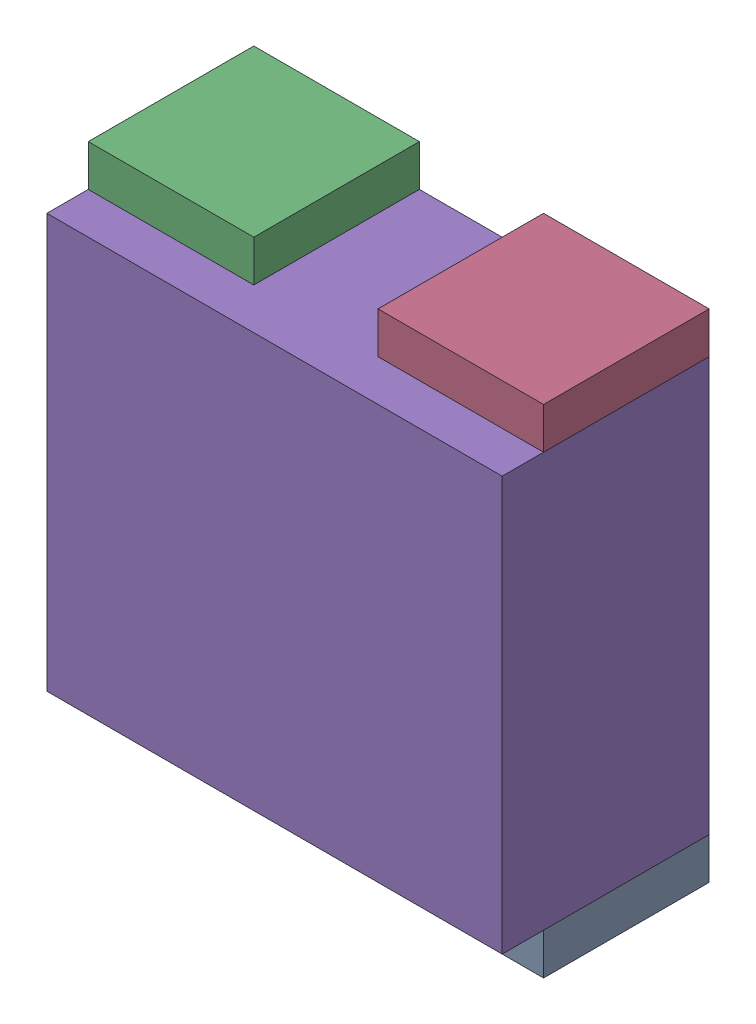
SolidWorks assembly RN12, configuration Default. Lengths in mm.
Overall size (1.1 1.2 0.5).
10 component instances, 2 part files, 0 mates.
Components (placement in the parent):
- 810157616-1: 810157616 [Default] at (123.35 53.35 0) size (0.4 0.1 0.4)
  - Extruded_12-1: Extruded_12 [Default] at origin size (0.4 0.1 0.4)
- 810157616-2: 810157616 [Default] at (122.65 53.35 0) size (0.4 0.1 0.4)
  - Extruded_12-1: Extruded_12 [Default] at origin size (0.4 0.1 0.4)
- 810157616-3: 810157616 [Default] at (122.65 54.45 0) size (0.4 0.1 0.4)
  - Extruded_12-1: Extruded_12 [Default] at origin size (0.4 0.1 0.4)
- 810157616-4: 810157616 [Default] at (123.35 54.45 0) size (0.4 0.1 0.4)
  - Extruded_12-1: Extruded_12 [Default] at origin size (0.4 0.1 0.4)
- 810156720-1: 810156720 [Default] at (123 53.9 0) size (1.1 1 0.5)
  - Extruded_13-1: Extruded_13 [Default] at origin size (1.1 1 0.5)
